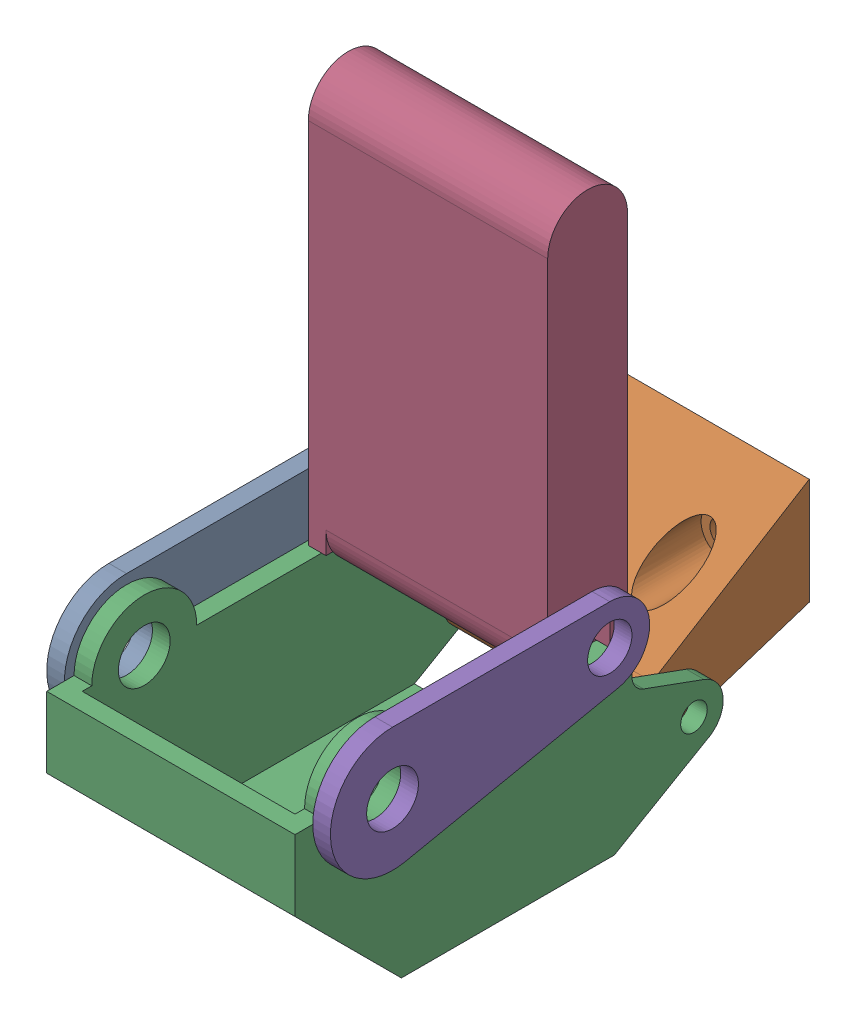
SolidWorks assembly Right Side Leg, configuration Default. Lengths in mm.
Overall size (25.81 53.23 49.2).
5 component instances, 4 part files, 12 mates.
Components (placement in the parent):
- Leg Attachment Part 1-1: Leg Attachment Part 1 [Default] at origin size (1.61 11.29 29.04)
- Leg Attachment Part 2-1: Leg Attachment Part 2 [Default] at (20.1638 -8.8722 -11.9323) size (17.74 13.72 15.56)
- Leg Attachment Part 3-1: Leg Attachment Part 3 [Default] at (0 -7.8816 1.351) x (0 0 -1) z (1 0 0) size (38.95 20.91 22.58)
- Leg Attachment Part 4-1: Leg Attachment Part 4 [Default] at (11.2916 17.7444 -5.3156) x (1 0 0) z (0 -1 0) size (21.78 7.26 38.71)
- Leg Attachment Part 1-2: Leg Attachment Part 1 [Default] at (24.196 0 0) size (1.61 11.29 29.04)
Mates (geometry in assembly coordinates):
- Concentric38: concentric: cylinder of assembly; cylinder of assembly; cylinder of Leg Attachment Part 1-1 through (-1.6129 0 14.4456) axis (1 0 0) radius 2.3546; cylinder of Leg Attachment Part 3-1 through (0 0 14.4456) axis (1 0 0) radius 2.3546
- Coincident45: coincident: plane of assembly; plane of assembly; plane of Leg Attachment Part 1-1 through (0 0 14.4456) normal (1 0 0); plane of Leg Attachment Part 3-1 through (0 0 14.4456) normal (-1 0 0)
- Parallel22: parallel: plane of assembly; plane of assembly; plane of Leg Attachment Part 1-1 through (-1.6129 5.6464 14.4456) normal (0 1 0); plane of Leg Attachment Part 1-2 through (22.5831 5.6464 14.4456) normal (0 1 0)
- Concentric39: concentric: cylinder of assembly; cylinder of assembly; cylinder of Leg Attachment Part 1-1 through (-1.6129 2.0168 -5.3156) axis (1 0 0) radius 2.0168; cylinder of Leg Attachment Part 4-1 through (0.4039 2.0168 -5.3156) axis (1 0 0) radius 2.0168
- Width18: width: plane of assembly; plane of assembly; plane of assembly; plane of assembly; plane of Leg Attachment Part 4-1 through (0.4039 2.0168 -5.3156) normal (-1 0 0); plane of Leg Attachment Part 4-1 through (22.1793 2.0168 -5.3156) normal (1 0 0); plane of Leg Attachment Part 1-1 through (0 0 14.4456) normal (1 0 0); plane of Leg Attachment Part 1-2 through (22.5831 0 14.4456) normal (-1 0 0)
- Width17: width: plane of assembly; plane of assembly; plane of assembly; plane of assembly; plane of Leg Attachment Part 2-1 through (2.4193 -8.8722 -14.5892) normal (-1 0 0); plane of Leg Attachment Part 2-1 through (20.1638 -8.8722 -14.5892) normal (1 0 0); plane of Leg Attachment Part 3-1 through (1.6129 0 14.4456) normal (1 0 0); plane of Leg Attachment Part 3-1 through (20.9702 0 14.4456) normal (-1 0 0)
- Concentric36: concentric: cylinder of assembly; cylinder of assembly; cylinder of Leg Attachment Part 2-1 through (2.4193 -8.8722 -14.5892) axis (1 0 0) radius 1.209; cylinder of Leg Attachment Part 3-1 through (0 -8.8722 -14.5892) axis (1 0 0) radius 1.209
- Parallel21: parallel: plane of assembly; plane of assembly; plane of Leg Attachment Part 2-1 through (2.4193 2.1895 -27.4949) normal (0 0 -1); plane of Leg Attachment Part 3-1 through (22.5831 0 21.7049) normal (0 0 1)
- Concentric37: concentric: cylinder of assembly; cylinder of assembly; cylinder of Leg Attachment Part 3-1 through (0 0 14.4456) axis (1 0 0) radius 2.3546; cylinder of Leg Attachment Part 1-2 through (22.5831 0 14.4456) axis (1 0 0) radius 2.3546
- Coincident44: coincident: plane of assembly; plane of assembly; plane of Leg Attachment Part 3-1 through (22.5831 0 14.4456) normal (1 0 0); plane of Leg Attachment Part 1-2 through (22.5831 0 14.4456) normal (-1 0 0)
- Parallel23: parallel: plane of assembly; plane of assembly; plane of Leg Attachment Part 3-1 through (22.5831 -16.1315 12.0275) normal (0 -1 0); plane of Leg Attachment Part 1-2 through (22.5831 5.6464 14.4456) normal (0 1 0)
- Coincident47: coincident: plane of assembly; plane of assembly; plane of Leg Attachment Part 3-1 through (22.5831 0 9.6704) normal (0 1 0); plane of Leg Attachment Part 4-1 through (20.5664 0 -1.686) normal (0 -1 0)
